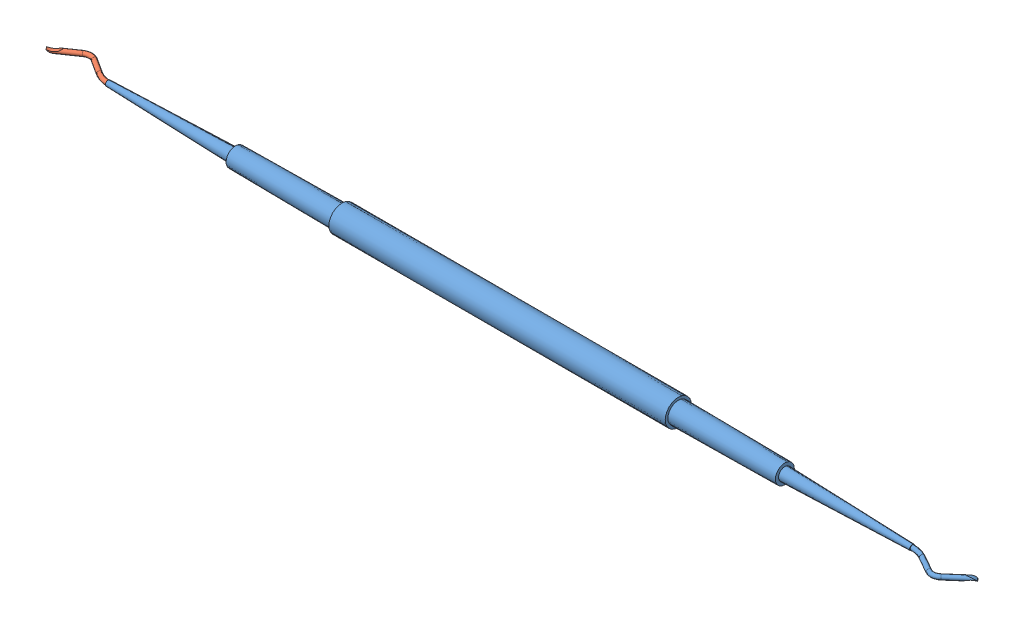
SolidWorks assembly Thomassin angled tip, configuration Default. Lengths in mm.
Overall size (176.24 5.21 6.79).
2 component instances, 2 part files, 2 mates.
Components (placement in the parent):
- Thomassin angled tip_one end-1: Thomassin angled tip_one end [Default] at (78.7079 90.8203 153.6274) size (164.59 5 5.5)
- Thomassin angled tip_other end-1: Thomassin angled tip_other end [Default] at (39.926 87.226 93.041) x (-0.997758 -0.003757 -0.066817) z (0.066923 -0.05601 -0.996185) size (11.92 2.95 4.48)
Mates (geometry in assembly coordinates):
- Coincident2: coincident anti-aligned: plane of Thomassin angled tip_one end-1 through (-18.2096 90.8203 121.3422) normal (-1 0 0); plane of Thomassin angled tip_other end-1 through (-18.2096 90.8203 121.3422) normal (1 0 0)
- Concentric1: concentric aligned: circle of Thomassin angled tip_one end-1; circle of Thomassin angled tip_other end-1
